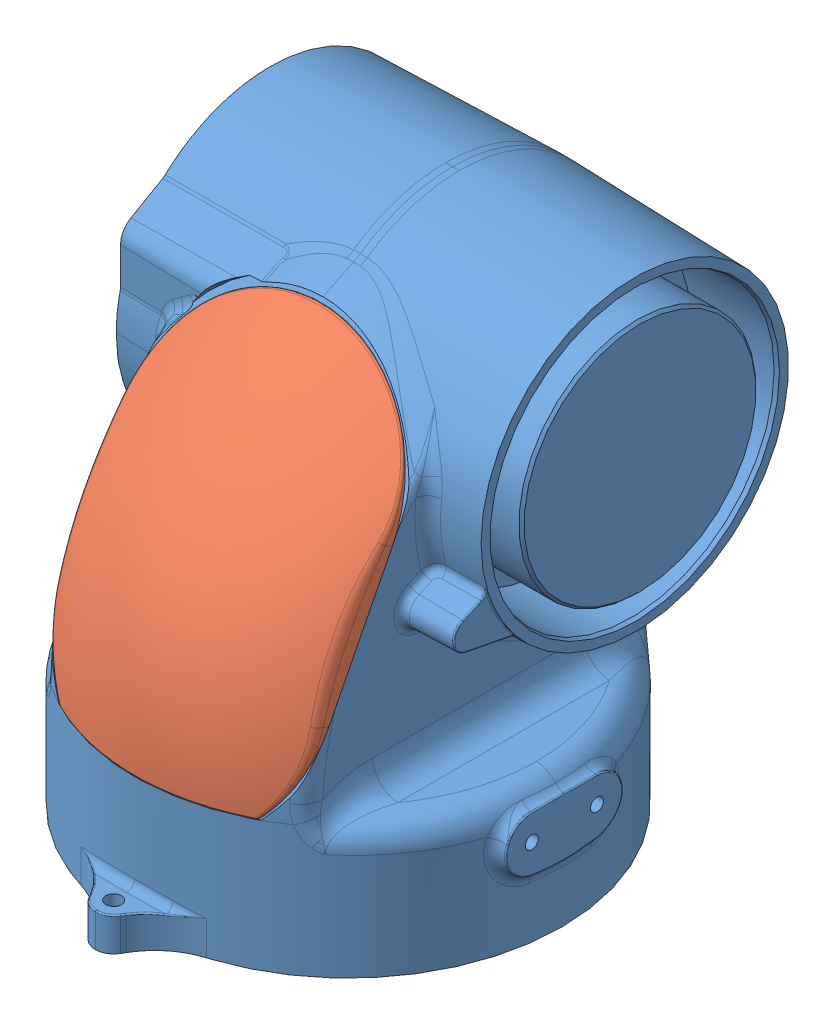
SolidWorks assembly GP7_S_AXIS, configuration Default. Lengths in mm.
Overall size (172.29 200.71 197.83).
3 component instances, 3 part files, 0 mates.
Components (placement in the parent):
- S-HEAD-1: S-HEAD [Default] at origin size (172.29 191.86 197.83)
- S_HEAD_COVER-1: S_HEAD_COVER [Default] at (0 -81 -19) x (0 -0.891007 0.45399) z (0 -0.45399 -0.891007) size (140.88 100.01 35.93)
- KU6BOLT_M8X16_SS_SSW-1: KU6BOLT_M8X16_SS_SSW [Default] at (0 -131.9 -52) x (-1 0 0) z (0 0 1) size (13.5 24 13.5)
